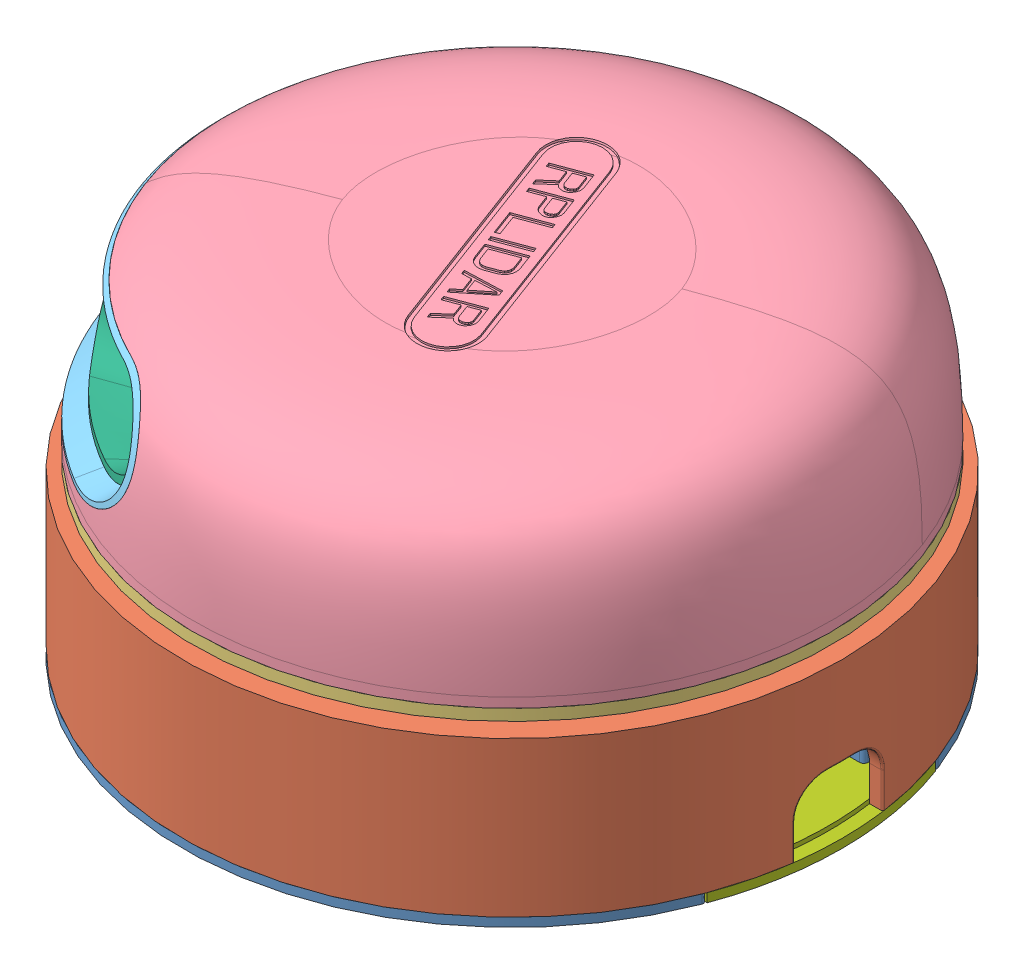
SolidWorks assembly RPLIDAR A2, configuration Défaut. Lengths in mm.
Overall size (149.2 40.81 94.01).
16 component instances, 15 part files, 0 mates.
Components (placement in the parent):
- µ×¸Ç-1: µ×¸Ç [Défaut] at (-6.0269 8.2139 75) size (72.54 3.5 75)
- ±àÂë³ÝÍâ¿Ç-1: ±àÂë³ÝÍâ¿Ç [Défaut] at (-6.0269 21.5139 75) size (75 18.2 75)
- Ðý×ªÆ½Ì¨-1: Ðý×ªÆ½Ì¨ [Défaut] at (-6.0269 28.0139 75) x (-0.350209 0 -0.936671) z (0.936671 0 -0.350209) size (72.5 4.01 72.5)
- LENS_1.6-1: LENS_1.6 [Défaut] at (-6.0269 21.5139 75) x (0.350209 0 0.936671) z (-0.936671 0 0.350209) size (72.5 20.11 74.54)
- KEY_1.6-1: KEY_1.6 [Défaut] at (-6.0269 21.5139 75) x (0.350209 0 0.936671) z (-0.936671 0 0.350209) size (60.14 14.27 29.34)
- BAT_COVER_19-1: BAT_COVER_19 [Défaut] at (-6.0269 21.5139 75) x (0.350209 0 0.936671) z (-0.936671 0 0.350209) size (56.56 17.71 24.64)
- ·â¸Ç-1: ·â¸Ç [Défaut] at (-6.0269 9.7139 75) x (0 0 -1) z (-1 0 0) size (26 1.5 12.5)
- ¼¤¹â·¢ÉäÍ·-1: ¼¤¹â·¢ÉäÍ· [Défaut] at (-8.2841 39.0139 48.9161) x (0.148651 0.950235 0.273781) z (-0.878816 0 0.477161) size (6 6 21.2)
- ¾µÍ·-1: ¾µÍ· [Défaut] at (-10.3767 39.0139 94.7757) x (0.331722 0.320609 0.887226) z (-0.936671 0 0.350209) size (14 14 11.5)
- Íâ½ÓÏßÕûÌå-1: Íâ½ÓÏßÕûÌå [Défaut] at (63.3713 -12.8505 75) size (86.12 10.5 15.7) (hidden)
  - 4pinÏßÀÂ-1: 4pinÏßÀÂ [Défaut] at (-33.3982 25.5643 0) size (47.5 6 9)
  - ½ÓÏß¶Ë¸Ç-1: ½ÓÏß¶Ë¸Ç [Défaut] at (-69.3982 22.0643 0) x (0 0 1) z (-1 0 0) size (15 10.5 3.83)
  - 6p ²åÍ·-1: 6p ²åÍ· [Défaut] at (-51.3982 24.9643 0) x (0 0 1) z (-1 0 0) size (13.7 5 6.45)
  - Áã¼þ4^Íâ½ÓÏßÕûÌå-1: Áã¼þ4^Íâ½ÓÏßÕûÌå [Défaut] at (-35.3982 25.5643 0) x (0 0 1) z (-1 0 0) size (11.49 4.16 15)
  - 5pin 2.54²åÍ·-1: 5pin 2.54²åÍ· [Défaut] at (22.0731 25.0643 -0.6) x (1 0 0) z (0 0 -1) size (8 5.5 15.2)
  - Áã¼þ1^Íâ½ÓÏßÕûÌå-1: Áã¼þ1^Íâ½ÓÏßÕûÌå [Défaut] at (22.0731 25.0643 -0.6) x (0 0 -1) z (-1 0 0) size (11.69 4.45 9.97)
